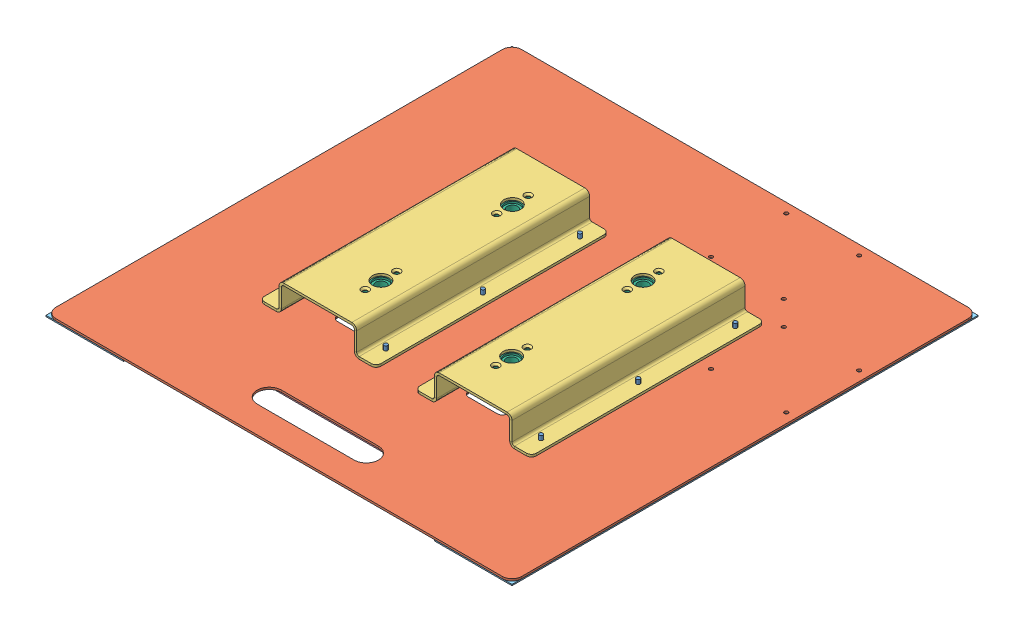
SolidWorks assembly FE-01021, configuration Default. Lengths in mm.
Overall size (609.6 41.15 609.6).
24 component instances, 6 part files, 24 mates.
Components (placement in the parent):
- FE-01020-1: FE-01020 [Default] at origin size (609.6 41.15 609.6)
  - rivet_.1875_.126-.25-21: rivet_.1875_.126-.25 [Default] at (128.2774 -1.1172 -107.7128) x (1 0 0) z (0 -1 0) size (10.01 10.01 13.03)
  - rivet_.1875_.126-.25-22: rivet_.1875_.126-.25 [Default] at (1.2774 -1.1172 -107.7128) x (0.982082 0 -0.188455) z (0 -1 0) size (10.01 10.01 13.03)
  - rivet_.1875_.126-.25-24: rivet_.1875_.126-.25 [Default] at (1.2774 -1.1172 19.2872) x (0.918365 0 -0.395734) z (0 -1 0) size (10.01 10.01 13.03)
  - rivet_.1875_.126-.25-26: rivet_.1875_.126-.25 [Default] at (128.2774 -1.1172 19.2872) x (0.8 0 -0.6) z (0 -1 0) size (10.01 10.01 13.03)
  - rivet_.1875_.126-.25-28: rivet_.1875_.126-.25 [Default] at (128.2774 -1.1172 146.2872) x (0.63358 0 -0.773678) z (0 -1 0) size (10.01 10.01 13.03)
  - rivet_.1875_.126-.25-30: rivet_.1875_.126-.25 [Default] at (1.2774 -1.1172 146.2872) x (0.443629 0 -0.896211) z (0 -1 0) size (10.01 10.01 13.03)
  - rivet_.1875_.126-.25-32: rivet_.1875_.126-.25 [Default] at (-74.9226 -1.1172 146.2872) x (0.263225 0 -0.964735) z (0 -1 0) size (10.01 10.01 13.03)
  - rivet_.1875_.126-.25-34: rivet_.1875_.126-.25 [Default] at (-201.9226 -1.1172 146.2872) x (0.120178 0 -0.992752) z (0 -1 0) size (10.01 10.01 13.03)
  - rivet_.1875_.126-.25-36: rivet_.1875_.126-.25 [Default] at (-74.9226 -1.1172 19.2872) x (0.030377 0 -0.999538) z (0 -1 0) size (10.01 10.01 13.03)
  - rivet_.1875_.126-.25-38: rivet_.1875_.126-.25 [Default] at (-201.9226 -1.1172 19.2872) x (0 0 -1) z (0 -1 0) size (10.01 10.01 13.03)
  - rivet_.1875_.126-.25-40: rivet_.1875_.126-.25 [Default] at (-74.9226 -1.1172 -107.7128) x (0.030377 0 -0.999538) z (0 -1 0) size (10.01 10.01 13.03)
  - rivet_.1875_.126-.25-42: rivet_.1875_.126-.25 [Default] at (-201.9226 -1.1172 -107.7128) x (0.120178 0 -0.992752) z (0 -1 0) size (10.01 10.01 13.03)
  - FE-01020-01-1: FE-01020-01 [Default] at (-36.8226 -1.1172 19.2872) size (609.6 2.66 609.6)
  - FE-01020-02-1: FE-01020-02 [Default] at (-138.4226 -2.8418 171.6872) x (0 0 -1) z (1 0 0) size (304.8 36.89 152.4)
  - FE-01020-02-2: FE-01020-02 [Default] at (64.7774 -2.8418 -133.1128) x (0 0 1) z (-1 0 0) size (304.8 36.89 152.4)
- Hook_4_16-1: Hook_4_16 [Default] at (-240.0226 -1.1172 -285.5128) size (406.4 1.59 101.6)
- Hook_4_16-2: Hook_4_16 [Default] at (-240.0226 -1.1172 155.8122) size (406.4 1.59 101.6)
- Hook_4_24-1: Hook_4_24 [Default] at (-240.0226 -1.1172 -285.5128) x (0 0 1) z (-1 0 0) size (609.6 1.59 101.6)
- Hook_4_24-2: Hook_4_24 [Default] at (267.9774 -1.1172 -285.5128) x (0 0 1) z (-1 0 0) size (609.6 1.59 101.6)
- nut_chassis_.625_11-1: nut_chassis_.625_11 [Default] at (48.9024 33.0039 -66.4378) x (0 0 -1) z (-1 0 0) size (57.15 15.88 25.4)
- nut_chassis_.625_11-2: nut_chassis_.625_11 [Default] at (48.9024 33.0039 105.5202) x (0 0 -1) z (-1 0 0) size (57.15 15.88 25.4)
- nut_chassis_.625_11-3: nut_chassis_.625_11 [Default] at (-122.5476 33.0039 -66.9458) x (0 0 -1) z (-1 0 0) size (57.15 15.88 25.4)
- nut_chassis_.625_11-4: nut_chassis_.625_11 [Default] at (-122.5476 33.0039 105.0122) x (0 0 -1) z (-1 0 0) size (57.15 15.88 25.4)
Mates (geometry in assembly coordinates):
- Coincident1: coincident: plane of FE-01020-1/FE-01020-01-1 through (-36.8226 -1.1172 19.2872) normal (0 -1 0); plane of Hook_4_24-1 through (-240.0226 -1.1172 -285.5128) normal (0 1 0)
- Coincident2: coincident: plane of FE-01020-1/FE-01020-01-1 through (-341.6226 1.5397 324.0872) normal (-1 0 0); plane of Hook_4_24-1 through (-341.6226 -2.7047 -285.5128) normal (-1 0 0)
- Coincident3: coincident aligned: plane of FE-01020-1/FE-01020-01-1 through (-341.6226 1.5397 324.0872) normal (0 0 1); plane of Hook_4_24-1 through (-240.0226 -2.7047 324.0872) normal (0 0 1)
- Coincident4: coincident: plane of FE-01020-1/FE-01020-01-1 through (-36.8226 -1.1172 19.2872) normal (0 -1 0); plane of Hook_4_24-2 through (267.9774 -1.1172 -285.5128) normal (0 1 0)
- Coincident5: coincident: plane of FE-01020-1/FE-01020-01-1 through (267.9774 1.5397 324.0872) normal (1 0 0); plane of Hook_4_24-2 through (267.9774 -2.7047 -285.5128) normal (1 0 0)
- Coincident6: coincident aligned: plane of FE-01020-1/FE-01020-01-1 through (-341.6226 1.5397 324.0872) normal (0 0 1); plane of Hook_4_24-2 through (267.9774 -2.7047 324.0872) normal (0 0 1)
- Coincident7: coincident: plane of FE-01020-1/FE-01020-01-1 through (-36.8226 -1.1172 19.2872) normal (0 -1 0); plane of Hook_4_16-2 through (-240.0226 -1.1172 155.8122) normal (0 1 0)
- Coincident8: coincident: plane of FE-01020-1/FE-01020-01-1 through (-100.3226 -1.1172 257.4122) normal (0 0 1); plane of Hook_4_16-2 through (-240.0226 -2.7047 257.4122) normal (0 0 1)
- Coincident9: coincident anti-aligned: plane of Hook_4_16-2 through (166.3774 -2.7047 155.8122) normal (1 0 0); plane of Hook_4_24-2 through (166.3774 -2.7047 -285.5128) normal (-1 0 0)
- Coincident10: coincident: plane of FE-01020-1/FE-01020-01-1 through (-36.8226 -1.1172 19.2872) normal (0 -1 0); plane of Hook_4_16-1 through (-240.0226 -1.1172 -285.5128) normal (0 1 0)
- Coincident11: coincident: plane of FE-01020-1/FE-01020-01-1 through (-341.6226 1.5397 -285.5128) normal (0 0 -1); plane of Hook_4_16-1 through (-240.0226 -2.7047 -285.5128) normal (0 0 -1)
- Coincident12: coincident anti-aligned: plane of Hook_4_16-1 through (-240.0226 -2.7047 -285.5128) normal (-1 0 0); plane of Hook_4_24-1 through (-240.0226 -2.7047 -285.5128) normal (1 0 0)
- Coincident13: coincident: plane of FE-01020-1/FE-01020-02-1 through (-93.9726 35.3852 -133.1128) normal (0 -1 0); plane of nut_chassis_.625_11-3 through (-122.5476 35.3852 -66.9458) normal (0 1 0)
- Coincident14: coincident: plane of FE-01020-1/FE-01020-02-1 through (-93.9726 35.3852 -133.1128) normal (0 -1 0); plane of nut_chassis_.625_11-4 through (-122.5476 35.3852 105.0122) normal (0 1 0)
- Coincident15: coincident: plane of FE-01020-1/FE-01020-02-2 through (20.3274 35.3852 171.6872) normal (0 -1 0); plane of nut_chassis_.625_11-2 through (48.9024 35.3852 105.5202) normal (0 1 0)
- Coincident16: coincident: plane of FE-01020-1/FE-01020-02-2 through (20.3274 35.3852 171.6872) normal (0 -1 0); plane of nut_chassis_.625_11-1 through (48.9024 35.3852 -66.4378) normal (0 1 0)
- Concentric1: concentric: circle of FE-01020-1/FE-01020-02-1; cylinder of nut_chassis_.625_11-3 through (-122.5476 19.5102 -87.5833) axis (0 1 0) radius 2.7781
- Concentric2: concentric aligned: circle of FE-01020-1/FE-01020-02-1; cylinder of nut_chassis_.625_11-3 through (-122.5476 19.5102 -46.3083) axis (0 1 0) radius 2.7781
- Concentric3: concentric: circle of FE-01020-1/FE-01020-02-1; cylinder of nut_chassis_.625_11-4 through (-122.5476 19.5102 84.3747) axis (0 1 0) radius 2.7781
- Concentric4: concentric aligned: circle of FE-01020-1/FE-01020-02-1; cylinder of nut_chassis_.625_11-4 through (-122.5476 19.5102 125.6497) axis (0 1 0) radius 2.7781
- Concentric5: concentric: circle of FE-01020-1/FE-01020-02-2; cylinder of nut_chassis_.625_11-2 through (48.9024 19.5102 84.8827) axis (0 1 0) radius 2.7781
- Concentric6: concentric aligned: circle of FE-01020-1/FE-01020-02-2; cylinder of nut_chassis_.625_11-2 through (48.9024 19.5102 126.1577) axis (0 1 0) radius 2.7781
- Concentric7: concentric: circle of FE-01020-1/FE-01020-02-2; cylinder of nut_chassis_.625_11-1 through (48.9024 19.5102 -87.0753) axis (0 1 0) radius 2.7781
- Concentric8: concentric aligned: circle of FE-01020-1/FE-01020-02-2; cylinder of nut_chassis_.625_11-1 through (48.9024 19.5102 -45.8003) axis (0 1 0) radius 2.7781
